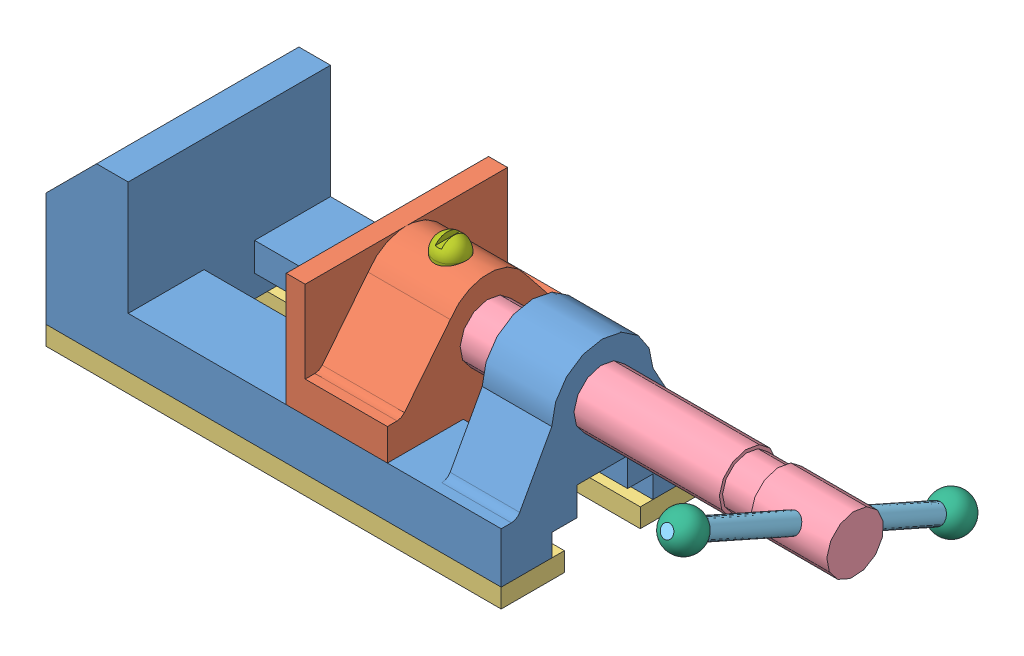
SolidWorks assembly Assem4, configuration Default. Lengths in mm.
Overall size (224 70.61 101.74).
9 component instances, 7 part files, 17 mates.
Components (placement in the parent):
- Part1-1: Part1 [Default] at (-7.3969 69.6844 -22.6802) size (144 52 64)
- Part2-1: Part2 [Default] at (-40.0871 37.0179 41.3198) x (-1 0 0) z (0 0 -1) size (32 45 64)
- Part3-1: Part3 [Default] at (-0.3182 -16.1728 -38.0949) x (1 0 0) z (0 1 0) size (144 20 6)
- Part3-2: Part3 [Default] at (-75.7595 -16.1728 56.7346) x (-1 0 0) z (0 1 0) size (144 20 6)
- Part4-1: Part4 [Default] at (50.6094 33.032 25.5599) x (1 0 0) z (0 0.914082 -0.40553) size (135 18 18)
- Part5-1: Part5 [Default] at (89.9318 39.6987 23.2352) x (0 0.40553 0.914082) z (-0.504913 -0.789008 0.350041) size (104 6 6)
- Part6-1: Part6 [Default] at (130.6159 -8.6084 -26.102) x (0.858555 -0.468669 0.207924) z (0.512721 0.78479 -0.348169) size (12 11.31 12)
- Part6-2: Part6 [Default] at (130.6159 28.9786 58.6208) x (0.858555 -0.468669 0.207924) z (-0.512721 -0.78479 0.348169) size (12 11.31 12)
- Part8-1: Part8 [Default] at (-14.0389 41.8272 9.3198) x (1 0 0) z (0 -1 0) size (10 10 14.9)
Mates (geometry in assembly coordinates):
- Width1: width aligned: plane of Part2-1 through (-40.0871 37.0179 41.3198) normal (0 0 1); plane of Part2-1 through (-40.0871 37.0179 -22.6802) normal (0 0 -1); plane of Part1-1 through (-119.8159 69.6844 1.3198) normal (0 0 1); plane of Part1-1 through (-119.8159 69.6844 17.3198) normal (0 0 -1)
- Coincident2: coincident anti-aligned: plane of Part1-1 through (-84.0389 5.8272 41.3198) normal (0 1 0); plane of Part2-1 through (-2.0389 5.8272 -22.6802) normal (0 -1 0)
- LimitDistance1: limit distance = 50 mm anti-aligned: plane of Part1-1 through (-84.0389 41.8272 41.3198) normal (1 0 0); plane of Part2-1 through (-34.0389 5.8272 -22.6802) normal (-1 0 0)
- Coincident3: coincident anti-aligned: plane of Part1-1 through (-110.0389 -10.1728 41.3198) normal (0 -1 0); plane of Part3-1 through (-0.3182 -10.1728 -38.0949) normal (0 1 0)
- Coincident4: coincident aligned: plane of Part1-1 through (33.9611 5.8272 41.3198) normal (1 0 0); plane of Part3-1 through (33.9611 -10.1728 41.3198) normal (1 0 0)
- Coincident5: coincident anti-aligned: plane of Part2-1 through (-2.0389 15.8272 -22.6802) normal (1 0 0); plane of Part4-1 through (-2.0389 33.032 25.5599) normal (-1 0 0)
- Concentric4: concentric anti-aligned: cylinder of Part1-1 through (-13.0389 25.8272 9.3198) axis (1 0 0) radius 8; cylinder of Part4-1 through (-33.3807 25.8272 9.3198) axis (-1 0 0) radius 9
- Screw2: screw = 0.5 anti-aligned: cylinder of Part1-1 through (-13.0389 25.8272 9.3198) axis (1 0 0) radius 8; cylinder of Part4-1 through (-33.3807 25.8272 9.3198) axis (-1 0 0) radius 9
- Concentric5: concentric: cylinder of Part4-1 through (125.2601 44.4704 -27.4583) axis (0 -0.452138 0.891948) radius 3; cylinder of Part5-1 through (125.2601 53.627 -45.5217) axis (0 0.452138 -0.891948) radius 3
- Concentric7: concentric: cylinder of Part4-1 through (125.2601 44.4704 -27.4583) axis (0 -0.452138 0.891948) radius 3; cylinder of Part5-1 through (125.2601 53.627 -45.5217) axis (0 0.452138 -0.891948) radius 3
- Concentric8: concentric anti-aligned: cylinder of Part4-1 through (101.9611 9.1058 -28.3709) axis (0 0.40553 0.914082) radius 3; cylinder of Part5-1 through (101.9611 0.8931 -46.8826) axis (0 -0.40553 -0.914082) radius 3
- Concentric9: concentric aligned: cylinder of Part5-1 through (101.9611 0.8931 -46.8826) axis (0 -0.40553 -0.914082) radius 2; cylinder of Part6-1 through (101.9611 10.4807 -25.2719) axis (0 -0.40553 -0.914082) radius 2
- Coincident6: coincident anti-aligned: circle of Part5-1; circle of Part6-1
- Coincident7: coincident anti-aligned: plane of Part2-1 through (-14.0389 39.8272 9.3198) normal (0 1 0); plane of Part8-1 through (-14.0389 39.8272 9.3198) normal (0 -1 0)
- Concentric11: concentric aligned: cylinder of Part2-1 through (-14.0389 32.8272 9.3198) axis (0 1 0) radius 3; cylinder of Part8-1 through (-14.0389 32.8272 9.3198) axis (0 1 0) radius 3
- Coincident8: coincident aligned: plane of Part1-1 through (-7.3969 69.6844 -22.6802) normal (0 0 -1); plane of Part3-2 through (33.9611 -10.1728 -22.6802) normal (0 0 -1)
- Distance1: distance = 43 mm aligned: plane of Part5-1 through (101.9611 4.7397 -38.2124) normal (0 -0.40553 -0.914082); cylinder of Part4-1 through (-33.3807 25.8272 9.3198) axis (-1 0 0) radius 9
